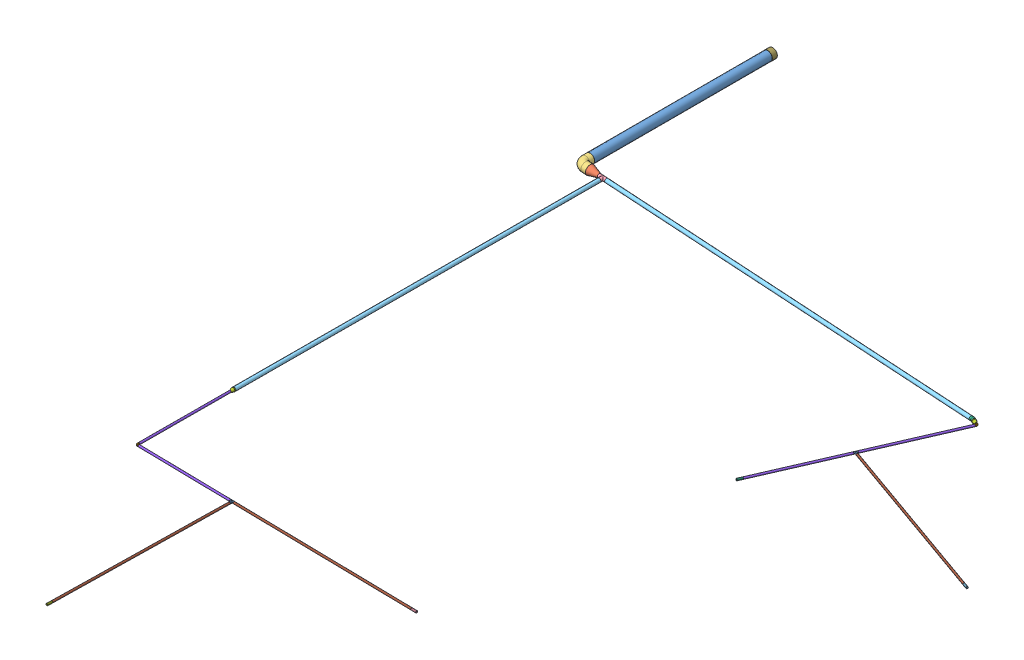
SolidWorks assembly Final_assembly, configuration Default. Lengths in mm.
Overall size (29900.71 1784.59 46152.04).
25 component instances, 16 part files, 23 mates.
Components (placement in the parent):
- 500 mm pipe-1: 500 mm pipe [Default] at (4505.7415 5444.5493 2114.4063) size (504 504 10000)
- 500 to 200-1: 500 to 200 [Default] at (5006.6984 5412.2041 12616.4063) x (0.997922 -0.064433 0) z (0 0 1) size (500 504 504)
- turn-pipe 500-1: turn-pipe 500 [Default] at (5006.6984 5412.2041 12616.4063) x (0 0 -1) z (0.064433 0.997922 0) size (753 753 502)
- 3 part 200 diam.-1: 3 part 200 diam. [Default] at (5505.7135 5380.8245 12816.4046) x (-0.00027 -0.004184 -0.999991) z (-0.064432 -0.997913 0.004193) size (301.19 400 202)
- 200mm diameter long pipe-1: 200mm diameter long pipe [Default] at (5705.2979 5367.938 12816.4046) x (1 -0.000001 -0.00027) z (0.00027 0.004184 0.999991) size (202 202 20000)
- 200mm diameter long pipe-2: 200mm diameter long pipe [Default] at (25863.2693 4065.5598 12616.4063) x (-0.054571 -0.845186 -0.531679) z (-0.997922 0.064433 0) size (202 202 20000)
- angle for 200 mm-1: angle for 200 mm [Default] at (25863.2693 4065.5598 12616.4063) x (0.997922 -0.064433 0) z (-0.064305 -0.995946 0.062899) size (228.51 230.11 202)
- 200 to 100 mm diameter-1: 200 to 100 mm diameter [Default] at (5613.5296 5479.1631 32816.1398) x (0.00027 0.004184 0.999991) z (0.272728 0.962083 -0.004099) size (200 202 202)
- 200 to 100 mm diameter-2: 200 to 100 mm diameter [Default] at (26058.8215 3955.5808 12634.052) x (0.939126 -0.039079 0.341343) z (-0.343085 -0.15956 0.925653) size (200 202 202)
- 100 mm short-1: 100 mm short [Default] at (5710.7549 5452.4545 33016.227) x (1 -0.000001 -0.00027) z (0.00027 0.004184 0.999991) size (102 102 5000)
- 100mm turn-2: 100mm turn [Default] at (26210.1773 4052.3136 12814.6272) x (0.939126 -0.039079 0.341343) z (0.053178 0.998071 -0.032041) size (153 153 102)
- 100 mm short-2: 100 mm short [Default] at (10813.2732 5380.1376 38117.196) x (0.00053 0.018352 0.999831) z (-0.999831 0.018358 0.000193) size (102 102 5000)
- 100mm turn-3: 100mm turn [Default] at (5814.0884 5471.5019 38016.1634) x (0.00027 0.004184 0.999991) z (-0.018357 -0.999823 0.004188) size (153 153 102)
- 100 mm short-3: 100 mm short [Default] at (26305.9681 4048.3275 12849.4442) x (0.940593 0.008443 0.339432) z (-0.339432 0.048242 0.939393) size (102 102 5000)
- 100mm 3 way-1: 100mm 3 way [Default] at (11013.2395 5376.4659 38117.1573) x (0.00053 0.018352 0.999831) z (-0.999831 0.018358 0.000193) size (201 102 200)
- 100mm 3 way-2: 100mm 3 way [Default] at (24608.8066 4289.5375 17546.4071) x (0.940593 0.008443 0.339432) z (-0.339432 0.048242 0.939393) size (201 102 200)
- long pipe 100 mm-1: long pipe 100 mm [Default] at (11012.3033 5325.4745 38117.1574) x (0.999831 -0.018358 -0.000193) z (0.000193 -0.000002 1) size (10000 102 102)
- long pipe 100 mm-2: long pipe 100 mm [Default] at (10914.2718 5330.0716 38268.0867) x (0.00053 0.018352 0.999831) z (-0.999831 -0.018339 0.000867) size (10000 102 102)
- 100 mm short-4: 100 mm short [Default] at (24540.9201 4299.1859 17734.2856) x (0.940593 0.008443 0.339432) z (-0.339432 0.048242 0.939393) size (102 102 5000)
- long pipe 100 mm-3: long pipe 100 mm [Default] at (24716.3828 4244.6301 17691.3365) x (0.940593 0.008443 0.339432) z (-0.339432 -0.001477 0.940629) size (10000 102 102)
- LID44-1: LID44 [Default] at origin size (514.15 514.15 275.06)
- LID45-1: LID45 [Default] at origin size (276.93 107.87 102.89)
- LID46-1: LID46 [Default] at origin size (294.55 105.49 190.11)
- LID47-1: LID47 [Default] at origin size (203.6 128.8 293.69)
- LID48-1: LID48 [Default] at origin size (106.02 110.9 276.91)
Mates (geometry in assembly coordinates):
- Concentric4: concentric anti-aligned: circle of 500 mm pipe-1; circle of turn-pipe 500-1
- Coincident1: coincident anti-aligned: plane of 500 mm pipe-1 through (4505.7415 5444.5493 12114.4063) normal (0 0 1); plane of turn-pipe 500-1 through (4505.7415 5444.5493 12114.4063) normal (0 0 -1)
- Coincident2: coincident anti-aligned: plane of 500 to 200-1 through (5006.6984 5412.2041 12616.4063) normal (-0.997922 0.064433 0); plane of turn-pipe 500-1 through (5006.6984 5412.2041 12616.4063) normal (0.997922 -0.064433 0)
- Concentric7: concentric aligned: circle of 500 to 200-1; circle of turn-pipe 500-1
- Concentric8: concentric anti-aligned: circle of 500 to 200-1; circle of 3 part 200 diam.-1
- Coincident3: coincident anti-aligned: plane of 500 to 200-1 through (5505.6594 5379.9877 12616.4063) normal (0.997922 -0.064433 0); plane of 3 part 200 diam.-1 through (5505.6594 5379.9877 12616.4063) normal (-0.997922 0.064433 0)
- Coincident4: coincident anti-aligned: circle of 3 part 200 diam.-1; circle of 200mm diameter long pipe-1
- Coincident5: coincident anti-aligned: circle of 3 part 200 diam.-1; circle of 200mm diameter long pipe-2
- Concentric9: concentric aligned: circle of 200mm diameter long pipe-2; circle of angle for 200 mm-1
- Coincident6: coincident anti-aligned: plane of 200mm diameter long pipe-2 through (25863.2693 4065.5598 12616.4063) normal (0.997922 -0.064433 0); plane of angle for 200 mm-1 through (25863.2693 4065.5598 12616.4063) normal (-0.997922 0.064433 0)
- Coincident7: coincident anti-aligned: circle of angle for 200 mm-1; circle of 200 to 100 mm diameter-2
- Coincident8: coincident anti-aligned: circle of 200mm diameter long pipe-1; circle of 200 to 100 mm diameter-1
- Coincident9: coincident anti-aligned: circle of 200 to 100 mm diameter-1; circle of 100 mm short-1
- Coincident12: coincident aligned: circle of 200 to 100 mm diameter-2; circle of 100mm turn-2
- Coincident14: coincident anti-aligned: circle of 100 mm short-1; circle of 100mm turn-3
- Coincident15: coincident aligned: circle of 100 mm short-2; circle of 100mm turn-3
- Coincident16: coincident anti-aligned: circle of 100mm turn-2; circle of 100 mm short-3
- Coincident17: coincident aligned: circle of 100 mm short-2; circle of 100mm 3 way-1
- Coincident18: coincident aligned: circle of 100 mm short-3; circle of 100mm 3 way-2
- Coincident19: coincident aligned: circle of 100mm 3 way-1; circle of long pipe 100 mm-1
- Coincident20: coincident anti-aligned: circle of 100mm 3 way-1; circle of long pipe 100 mm-2
- Coincident21: coincident aligned: circle of 100mm 3 way-2; circle of 100 mm short-4
- Coincident22: coincident anti-aligned: circle of 100mm 3 way-2; circle of long pipe 100 mm-3
